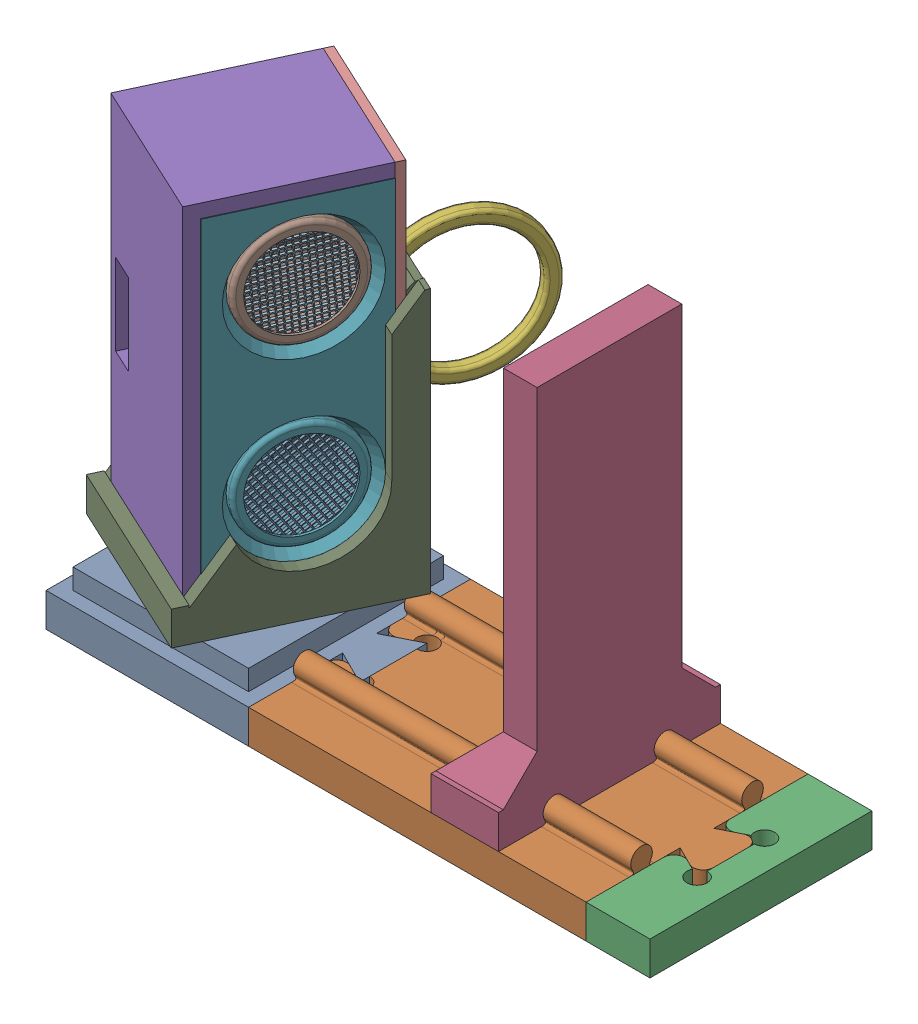
SolidWorks assembly 2.2.3.3.4_Medicion_Unidireccional_Distancia_Ultrasonido, configuration Predeterminado. Lengths in mm.
Overall size (114.02 83.27 83.27).
12 component instances, 10 part files, 2 mates.
Components (placement in the parent):
- 2.2.2.1_Mono_Guia_Lineal-1: 2.2.2.1_Mono_Guia_Lineal [Predeterminado] at (10.1898 -43.4745 33.6632) size (89.47 61.68 32.88)
  - 2.1.2.2.6_Base_Sujetador-1: 2.1.2.2.6_Base_Sujetador [Predeterminado] at (-44.4459 -5.7383 3.6115) x (-1 0 0) z (0 -1 0) size (35 32.88 8)
  - 2.1.2.2.7_Segmento_Riel-1: 2.1.2.2.7_Segmento_Riel [Predeterminado] at (-54.4459 -13.7383 3.6115) x (-1 0 0) z (0 -1 0) size (55.01 32.88 8.1)
  - 2.1.2.2.8_Segmento_Final_De_Riel-1: 2.1.2.2.8_Segmento_Final_De_Riel [Predeterminado] at (-54.4459 -13.7383 3.6115) x (-1 0 0) z (0 -1 0) size (9.47 32.88 5)
  - 2.1.2.2.9_Pared_De_Rebote-1: 2.1.2.2.9_Pared_De_Rebote [Predeterminado] at (-3.4196 -13.7383 3.6115) x (0 -1 0) z (1 0 0) size (56.68 32.88 10.01)
- 2.2.2.3_Caja_Ultrasonido-1: 2.2.2.3_Caja_Ultrasonido [Predeterminado] at (-69.7343 -12.876 -48.1277) x (0.419215 0.247516 0.873495) z (-0.884397 0.328775 0.331285) size (50.29 75.57 55.67)
  - 2.1.2.2.3_Cubierta_Posterior-1: 2.1.2.2.3_Cubierta_Posterior [Predeterminado] at (89.0125 -31.8608 0.2222) x (-0.247516 -0.911396 -0.328775) z (0.748898 0.035331 -0.661743) size (52.81 23.68 22)
  - 2.1.2.2.1_Manija-1: 2.1.2.2.1_Manija [Predeterminado] at (88.4905 -14.7597 21.6451) x (0.614726 -0.410011 0.673798) z (0.748898 0.035331 -0.661743) size (42.87 46.77 2.06)
  - 2.1.2.2.2_Cubierta_Frontal-1: 2.1.2.2.2_Cubierta_Frontal [Predeterminado] at (78.3032 -32.366 9.6851) x (0.247516 0.911396 0.328775) z (0.614726 -0.410011 0.673798) size (48.81 9.5 21.68)
  - HC-SR04.stp-1: HC-SR04.stp [Predeterminado] at (75.213 -29.0582 6.2192) x (-0.247516 -0.911396 -0.328775) z (0.748898 0.035331 -0.661743) size (45.62 20.4 15.39)
  - 2.1.2.2.5_Sujetador-1: 2.1.2.2.5_Sujetador [Predeterminado] at (82.4771 -55.9253 -8.4588) x (-0.748898 -0.035331 0.661743) z (-0.247516 -0.911396 -0.328775) size (26 28.88 48.33)
  - 2.1.2.2.4_Cubierta_Superior-1: 2.1.2.2.4_Cubierta_Superior [Predeterminado] at (65.6879 -24.0053 -3.9942) x (-0.247516 -0.911396 -0.328775) z (-0.614726 0.410011 -0.673798) size (52.81 22 15.2)
Mates (geometry in assembly coordinates):
- Concéntrica9: concentric aligned: cylinder of 2.2.2.1_Mono_Guia_Lineal-1/2.1.2.2.6_Base_Sujetador-1 through (-45.2561 -52.2128 28.1171) axis (0 1 0) radius 8; cylinder of Ensamblaje2^Ensamblaje1-1/2.1.2.2.5_Sujetador-1 through (-45.2561 -57.2128 28.1171) axis (0 1 0) radius 8
- Coincidente11: coincident aligned: plane of 2.2.2.1_Mono_Guia_Lineal-1/2.1.2.2.6_Base_Sujetador-1 through (-34.2561 -57.2128 37.2747) normal (0 -1 0); plane of Ensamblaje2^Ensamblaje1-1/2.1.2.2.5_Sujetador-1 through (-45.2561 -57.2128 28.1171) normal (0 -1 0)
